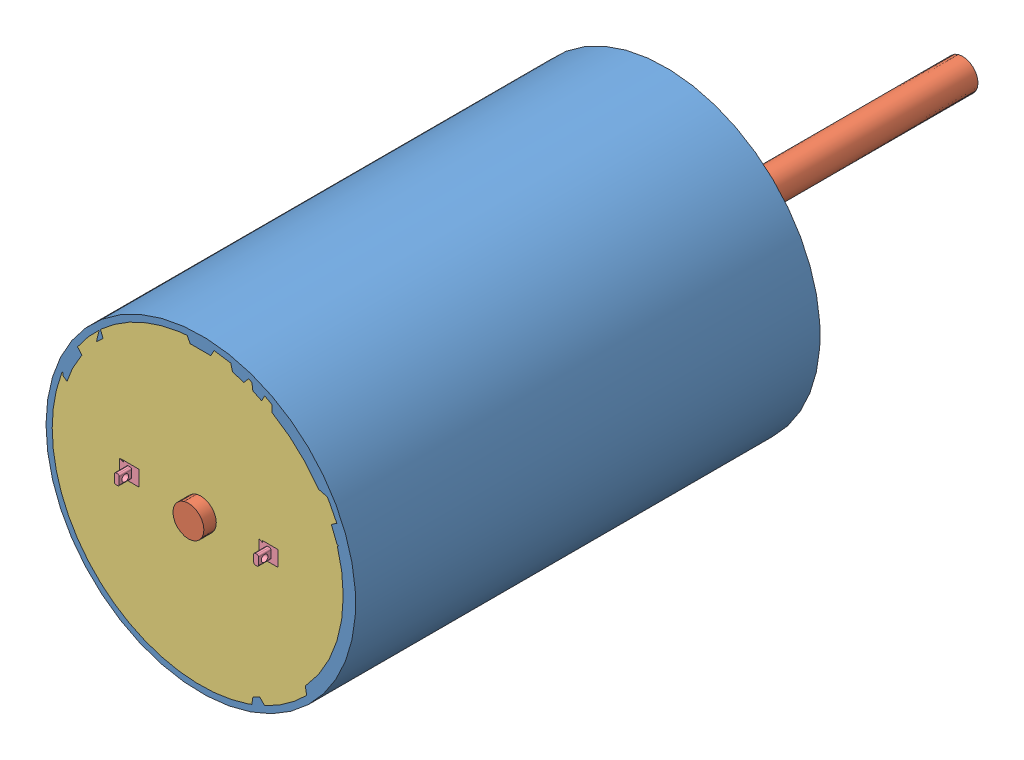
SolidWorks assembly Motor, configuration Default. Lengths in mm.
Overall size (20 20 50).
5 component instances, 4 part files, 9 mates.
Components (placement in the parent):
- motorcover-1: motorcover [Default] at (7.4227 18.4991 11.7262) size (20 20 32)
- dynamo-1: dynamo [Default] at (7.4227 18.4991 32.5262) x (0.962292 0.27202 0) z (0 0 -1) size (15 15 50)
- Backcover-1: Backcover [Default] at (7.4227 18.4991 40.9262) size (19.2 19.2 0.8)
- pin-1: pin [Default] at (28.5286 14.4912 41.7262) x (1 0 0) z (0 0 -1) size (1.25 1 1.6)
- pin-2: pin [Default] at (37.5286 14.4917 41.7262) x (1 0 0) z (0 0 -1) size (1.25 1 1.6)
Mates (geometry in assembly coordinates):
- Concentric1: concentric: circle of assembly; circle of motorcover-1; circle of dynamo-1
- Coincident1: coincident anti-aligned: plane of motorcover-1 through (7.4227 18.4991 12.5262) normal (0 0 1); plane of dynamo-1 through (7.4227 18.4991 12.5262) normal (0 0 -1)
- Concentric2: concentric aligned: circle of motorcover-1; circle of Backcover-1
- Coincident2: coincident aligned: line of Backcover-1 through (3.4227 18.9991 40.9262) axis (0 -1 0); line of pin-1 through (3.4227 18.9991 40.9262) axis (0 -1 0)
- Coincident3: coincident aligned: line of Backcover-1 through (2.4227 18.9991 40.9262) axis (1 0 0); line of pin-1 through (2.1727 18.9991 40.9262) axis (1 0 0)
- Concentric3: concentric aligned: circle of motorcover-1; circle of Backcover-1
- Coincident4: coincident aligned: plane of motorcover-1 through (7.4227 18.4991 41.7262) normal (0 0 1); plane of Backcover-1 through (7.4227 18.4991 41.7262) normal (0 0 1)
- Coincident5: coincident aligned: line of Backcover-1 through (12.4227 18.9991 40.9262) axis (0 -1 0); line of pin-2 through (12.4227 18.9996 40.9262) axis (0 -1 0)
- Parallel1: parallel aligned: line of Backcover-1 through (11.4227 18.9991 40.9262) axis (1 0 0); line of pin-2 through (11.1727 18.9996 41.7262) axis (1 0 0)
